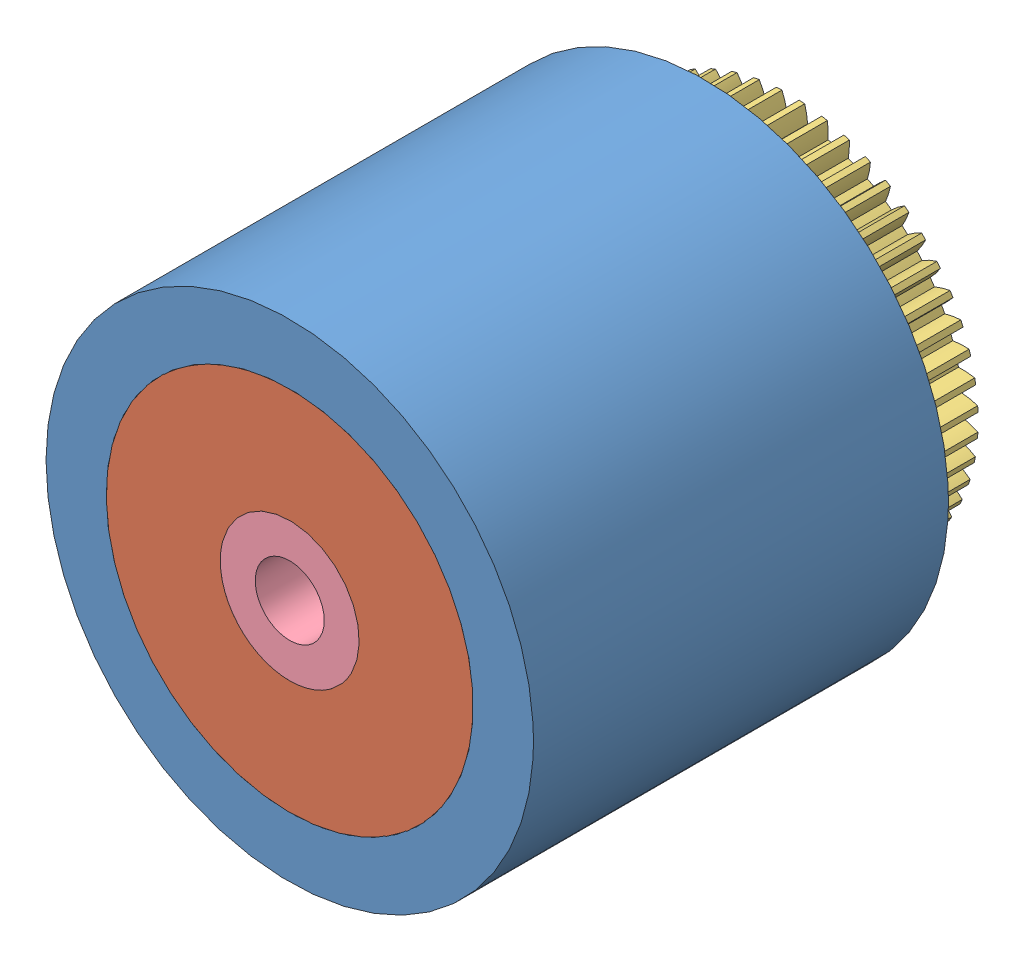
SolidWorks assembly Llanta, configuration Predeterminado. Lengths in mm.
Overall size (59.21 59.21 57.2).
5 component instances, 4 part files, 8 mates.
Components (placement in the parent):
- Latex-1: Latex [Predeterminado] at (2.7474 1.7171 32.05) size (55.8 55.8 47.5)
- rine-1: rine [Predeterminado] at (2.7474 1.7171 30.05) x (0.649292 0.76054 0) z (0 0 1) size (42 42 57)
- Gear_52T-1: Gear_52T [Predeterminado] at (2.7474 1.7171 28.85) x (0 0 -1) z (0.999983 -0.0058 0) size (6.5 43.16 43.16)
- opresor-1: opresor [Predeterminado] at (2.7474 1.7171 22.55) size (15.9 15.9 6.35)
- opresor-2: opresor [Predeterminado] at (2.7474 1.7171 73.2) size (15.9 15.9 6.35)
Mates (geometry in assembly coordinates):
- Concéntrica1: concentric: cylinder of Latex-1 through (2.7474 1.7171 79.55) axis (0 0 -1) radius 21; cylinder of rine-1 through (2.7474 1.7171 79.55) axis (0 0 -1) radius 21
- Coincidente1: coincident: plane of Latex-1 through (2.7474 1.7171 79.55) normal (0 0 1); plane of rine-1 through (2.7474 1.7171 79.55) normal (0 0 1)
- Concéntrica2: concentric: cylinder of rine-1 through (2.7474 1.7171 79.55) axis (0 0 -1) radius 3.9; cylinder of Gear_52T-1 through (2.7474 1.7171 28.85) axis (0 0 1) radius 17.3
- Distancia2: distance = 1.2 mm: plane of Gear_52T-1 through (2.7474 1.7171 28.85) normal (0 0 1); plane of rine-1 through (2.7474 1.7171 30.05) normal (0 0 -1)
- Concéntrica3: concentric: cylinder of rine-1 through (2.7474 1.7171 73.2) axis (0 0 1) radius 7.95; cylinder of opresor-2 through (2.7474 1.7171 73.2) axis (0 0 1) radius 3.95
- Coincidente4: coincident: plane of rine-1 through (2.7474 1.7171 79.55) normal (0 0 1); plane of opresor-2 through (2.7474 1.7171 79.55) normal (0 0 1)
- Concéntrica4: concentric: cylinder of rine-1 through (2.7474 1.7171 28.9) axis (0 0 -1) radius 7.95; cylinder of opresor-1 through (2.7474 1.7171 22.55) axis (0 0 1) radius 3.95
- Coincidente5: coincident: plane of rine-1 through (2.7474 1.7171 22.55) normal (0 0 -1); plane of opresor-1 through (2.7474 1.7171 22.55) normal (0 0 -1)
